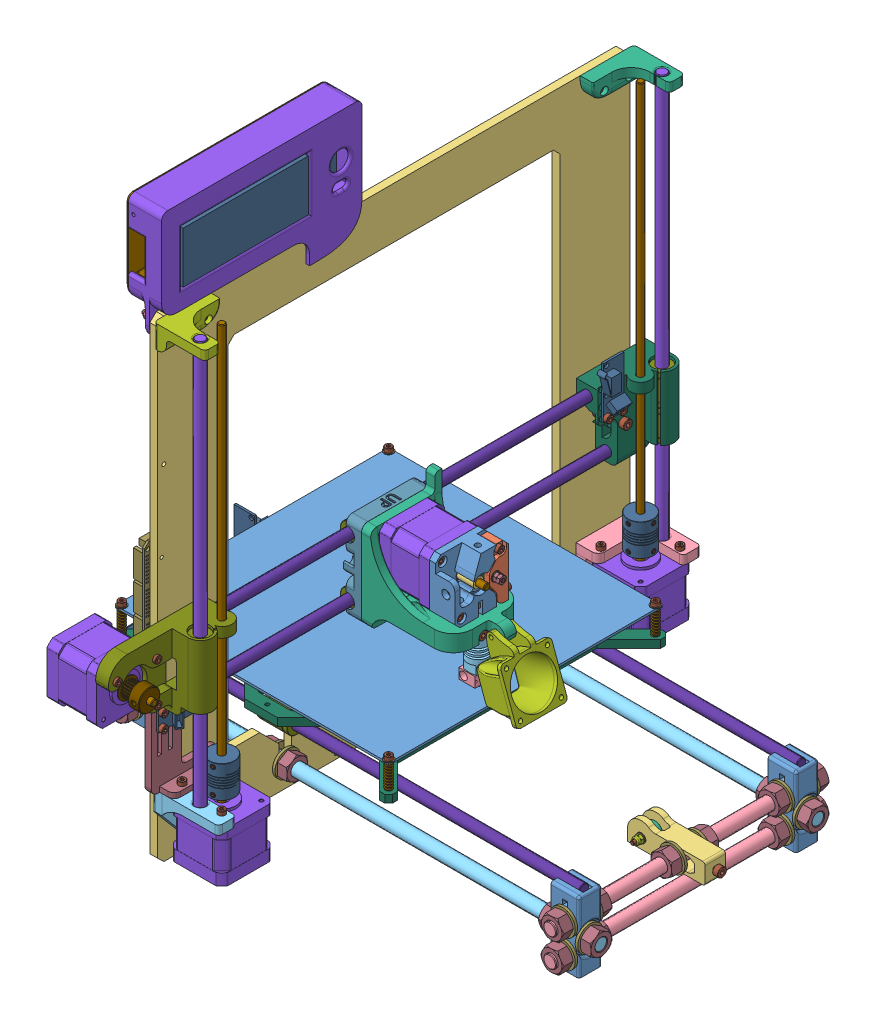
SolidWorks assembly PRUSAI3, configuration Default. Lengths in mm.
Overall size (404.17 477.46 509.56).
242 component instances, 46 part files, 23 mates.
Components (placement in the parent):
- Base-1: Base [Default] at origin size (404.17 86.77 210.4)
  - Base_corner-0.1-1: Base_corner-0.1 [Default] at origin size (22 55 18)
  - Base_corner-0.1-2: Base_corner-0.1 [Default] at (-318 0 -18) x (-1 0 0) z (0 0 -1) size (22 55 18)
  - Base_corner-0.1-3: Base_corner-0.1 [Default] at (0 0 -170) size (22 55 18)
  - Base_corner-0.1-4: Base_corner-0.1 [Default] at (-318 0 -188) x (-1 0 0) z (0 0 -1) size (22 55 18)
  - motor-holder.mod-1: motor-holder.mod [Default] at (-374.7251 51.5513 -101.8541) x (1 0 0) z (0 0 -1) size (87.93 49.87 10)
  - motor-idler.mod-1: motor-idler.mod [Default] at (-14.7612 34.4184 -85.8494) x (0 0 -1) z (0.003191 0.999995 0) size (16.01 60.81 19.45)
  - M10x210-Threaded_Rod-1: M10x210-Threaded_Rod [Default] at (-329 12 12) x (0.934388 0.356257 0) z (0 0 1) size (10 10 210)
  - M10x210-Threaded_Rod-2: M10x210-Threaded_Rod [Default] at (11 12 12) x (0.968928 -0.247345 0) z (0 0 1) size (10 10 210)
  - M10x210-Threaded_Rod-3: M10x210-Threaded_Rod [Default] at (11 34 12) size (10 10 210)
  - M10x210-Threaded_Rod-4: M10x210-Threaded_Rod [Default] at (-329 34 12) x (-0.101096 0.994877 0) z (0 0 1) size (10 10 210)
  - M10x380-Th_Rod-1: M10x380-Th_Rod [Default] at (30 23 -179) x (0 -0.123501 0.992344) z (1 0 0) size (10 10 380)
  - M10x380-Th_Rod-2: M10x380-Th_Rod [Default] at (30 23 -9) x (0 -0.445891 -0.895087) z (1 0 0) size (10 10 380)
  - 4mm Bearing SKF 624 RS 286-7798-1: 4mm Bearing SKF 624 RS 286-7798 [Default] at (-14.7612 34.4184 -96.1602) x (0 0 -1) z (0.767407 -0.641161 0) size (5 13 13)
  - Locking nut-1: Locking nut [DIN EN ISO 7040 - M3 - N] at (-14.7612 34.4184 -82.6956) x (0.998707 -0.050831 0) z (0 0 1) size (5.5 6.35 4.5)
  - Stepper_motor_NEMA17 39mm-1: Stepper_motor_NEMA17 39mm [Default] at (-296.4022 27.5 -99.8541) x (1 0 0) z (0 -1 0) size (42 63.3 42)
    - Stator-1: Stator [Default] at origin size (42 41.1 42)
    - Rotor-1: Rotor [Default] x (0.508449 0 0.861092) z (-0.861092 0 0.508449) size (21 60.8 21)
  - Mech endstop-1: Mech endstop [Default] at (-342.0588 64.8904 -101.8541) x (0 1 0) z (0 0 -1) size (40 21.02 12.37)
  - Socket head cap screw-2: Socket head cap screw [M3x25] at (-14.7612 34.4184 -106.281) x (0 0 1) z (0.238463 0.971152 0) size (28 5.5 5.5)
  - Socket head cap screw-1: Socket head cap screw [DIN 912 M4 x 20 --- 20N] at (40.3236 34.2427 -93.8494) x (-0.999995 0.003191 0) z (0.002674 0.838028 0.545621) size (24 7 7)
  - Socket head cap screw-3: Socket head cap screw [M3x12] at (-311.9022 43 -90.8541) x (0 0 -1) z (0.820112 0.572203 0) size (15 5.5 5.5)
  - Socket head cap screw-4: Socket head cap screw [M3x12] at (-311.9022 12 -90.8541) x (0 0 -1) z (1 0 0) size (15 5.5 5.5)
  - Socket head cap screw-5: Socket head cap screw [M3x12] at (-280.9022 12 -90.8541) x (0 0 -1) z (1 0 0) size (15 5.5 5.5)
  - Socket head cap screw-6: Socket head cap screw [M3x10] at (-336.5588 47.3904 -106.4541) x (0 0 1) z (-1 0 0) size (13 5.5 5.5)
  - Socket head cap screw-7: Socket head cap screw [M3x10] at (-347.5588 47.3904 -106.4541) x (0 0 1) z (-1 0 0) size (13 5.5 5.5)
  - Plain washer-1: Plain washer [M3 plain washer] at (-14.7612 34.4184 -85.5697) x (0 0 -1) z (0.726093 -0.687596 0) size (0.5 7 7)
  - Plain washer-2: Plain washer [M3 plain washer] at (-14.7612 34.4184 -100.668) x (0 0 -1) z (0.875249 -0.483673 0) size (0.5 7 7)
  - Plain washer-3: Plain washer [M10 plain washer] at (-224 23 -179) x (1 0 0) z (0 0.48884 0.872373) size (2 20 20)
  - Plain washer-4: Plain washer [M10 plain washer] at (0 23 -179) x (1 0 0) z (0 -0.109422 0.993995) size (2 20 20)
  - Plain washer-5: Plain washer [M10 plain washer] at (-216 23 -179) x (1 0 0) z (0 -0.107778 0.994175) size (2 20 20)
  - Plain washer-6: Plain washer [M10 plain washer] at (-316 23 -179) x (1 0 0) z (0 -0.430378 0.902649) size (2 20 20)
  - Plain washer-7: Plain washer [M10 plain washer] at (22 23 -179) x (1 0 0) z (0 -0.121982 0.992532) size (2 20 20)
  - Plain washer-8: Plain washer [M10 plain washer] at (-338 23 -179) x (1 0 0) z (0 -0.100121 0.994975) size (2 20 20)
  - Plain washer-15: Plain washer [M10 plain washer] at (11 34 -188) x (0 0 1) z (-0.882764 0.469816 0) size (2 20 20)
  - Plain washer-16: Plain washer [M10 plain washer] at (11 34 2) x (0 0 1) z (-0.957093 -0.28978 0) size (2 20 20)
  - Plain washer-17: Plain washer [M10 plain washer] at (11 12 -18) x (0 0 1) z (-0.957093 -0.28978 0) size (2 20 20)
  - Plain washer-18: Plain washer [M10 plain washer] at (11 34 -168) x (0 0 1) z (-0.809211 -0.587518 0) size (2 20 20)
  - Plain washer-19: Plain washer [M10 plain washer] at (11 34 -101.8494) x (0 0 1) z (-0.957093 -0.28978 0) size (2 20 20)
  - Plain washer-20: Plain washer [M10 plain washer] at (11 12 -168) x (0 0 1) z (-0.952122 -0.305719 0) size (2 20 20)
  - Plain washer-21: Plain washer [M10 plain washer] at (11 12 -188) x (0 0 1) z (-0.957093 -0.28978 0) size (2 20 20)
  - Plain washer-22: Plain washer [M10 plain washer] at (11 34 -18) x (0 0 1) z (-0.957093 -0.28978 0) size (2 20 20)
  - Plain washer-23: Plain washer [M10 plain washer] at (11 34 -83.8494) x (0 0 1) z (-0.957093 -0.28978 0) size (2 20 20)
  - Plain washer-24: Plain washer [M10 plain washer] at (11 12 2) x (0 0 1) z (-0.957093 -0.28978 0) size (2 20 20)
  - Plain washer-33: Plain washer [M10 plain washer] at (-329 12 -102.0906) x (0 0 1) z (-0.8302 -0.557466 0) size (2 20 20)
  - Plain washer-34: Plain washer [M10 plain washer] at (-329 34 -101.8541) x (0 0 1) z (-0.803588 0.595186 0) size (2 20 20)
  - Plain washer-35: Plain washer [M10 plain washer] at (-329 34 -89.8541) x (0 0 1) z (-0.998096 0.061678 0) size (2 20 20)
  - Plain washer-36: Plain washer [M10 plain washer] at (-329 12 -89.5517) x (0 0 1) z (-0.979431 0.201779 0) size (2 20 20)
  - Plain washer-39: Plain washer [M10 plain washer] at (-329 12 -188) x (0 0 1) z (-0.957093 -0.28978 0) size (2 20 20)
  - Plain washer-40: Plain washer [M10 plain washer] at (-329 34 -188) x (0 0 1) z (-0.957093 -0.28978 0) size (2 20 20)
  - Plain washer-41: Plain washer [M10 plain washer] at (-329 12 -168) x (0 0 1) z (-0.957093 -0.28978 0) size (2 20 20)
  - Plain washer-42: Plain washer [M10 plain washer] at (-329 34 -168) x (0 0 1) z (-0.957093 -0.28978 0) size (2 20 20)
  - Plain washer-47: Plain washer [M10 plain washer] at (-223.0717 23 -9) x (1 0 0) z (0 -0.28978 0.957093) size (2 20 20)
  - Plain washer-48: Plain washer [M10 plain washer] at (-215.0717 23 -9) x (1 0 0) z (0 -0.28978 0.957093) size (2 20 20)
  - Plain washer-43: Plain washer [M10 plain washer] at (-329 12 -18) x (0 0 1) z (-0.957093 -0.28978 0) size (2 20 20)
  - Plain washer-44: Plain washer [M10 plain washer] at (-329 34 -18) x (0 0 1) z (-0.957093 -0.28978 0) size (2 20 20)
  - Plain washer-45: Plain washer [M10 plain washer] at (-329 12 2) x (0 0 1) z (-0.957093 -0.28978 0) size (2 20 20)
  - Plain washer-46: Plain washer [M10 plain washer] at (-329 34 2) x (0 0 1) z (-0.957093 -0.28978 0) size (2 20 20)
  - Plain washer-37: Plain washer [M10 plain washer] at (11 12 -18) x (0 0 1) z (-0.957093 -0.28978 0) size (2 20 20)
  - Hex nut-1: Hex nut [M4 Hex Nut] at (21.2099 34.3037 -93.8494) x (0.001311 0.410701 0.911769) z (-0.999995 0.003191 0) size (7 8.08 3.2)
  - Hex nut-2: Hex nut [M3 Hex Nut] at (-336.5588 47.3904 -94.0203) x (0.985742 0.168264 0) z (0 0 1) size (5.5 6.35 2.4)
  - Hex nut-3: Hex nut [M3 Hex Nut] at (-347.5588 47.3904 -93.992) x (0.630761 -0.775977 0) z (0 0 1) size (5.5 6.35 2.4)
  - Hex nut-4: Hex nut [M10 Hex Nut] at (-329 12 -81.1517) x (0.998444 0.055764 0) z (0 0 1) size (16 18.48 8.4)
  - Hex nut-5: Hex nut [M10 Hex Nut] at (-329 34 -103.8541) x (0.98326 0.182209 0) z (0 0 1) size (16 18.48 8.4)
  - Hex nut-6: Hex nut [M10 Hex Nut] at (-329 34 -81.4541) size (16 18.48 8.4)
  - Hex nut-7: Hex nut [M10 Hex Nut] at (-329 12 -104.0906) x (0.982431 -0.186624 0) z (0 0 1) size (16 18.48 8.4)
  - Hex nut-8: Hex nut [M10 Hex Nut] at (-329 12 -159.6) x (0.697574 0.716512 0) z (0 0 1) size (16 18.48 8.4)
  - Hex nut-9: Hex nut [M10 Hex Nut] at (-329 34 10.4) x (0.514033 0.85777 0) z (0 0 1) size (16 18.48 8.4)
  - Hex nut-10: Hex nut [M10 Hex Nut] at (-329 12 -20) x (0.882857 0.469642 0) z (0 0 1) size (16 18.48 8.4)
  - Hex nut-11: Hex nut [M10 Hex Nut] at (-329 12 10.4) x (0.513305 0.858206 0) z (0 0 1) size (16 18.48 8.4)
  - Hex nut-12: Hex nut [M10 Hex Nut] at (-329 34 -20) x (0.752342 0.658773 0) z (0 0 1) size (16 18.48 8.4)
  - Hex nut-13: Hex nut [M10 Hex Nut] at (-329 12 -190) x (0.72852 0.685024 0) z (0 0 1) size (16 18.48 8.4)
  - Hex nut-14: Hex nut [M10 Hex Nut] at (-329 34 -159.6) x (0.559236 0.829009 0) z (0 0 1) size (16 18.48 8.4)
  - Hex nut-15: Hex nut [M10 Hex Nut] at (-329 34 -190) x (-0.791014 0.611798 0) z (0 0 1) size (16 18.48 8.4)
  - Hex nut-24: Hex nut [M10 Hex Nut] at (-234.4 23 -179) x (0 -0.116344 0.993209) z (-1 0 0) size (16 18.48 8.4)
  - Hex nut-25: Hex nut [M10 Hex Nut] at (-316 23 -9) x (0 -0.002508 0.999997) z (-1 0 0) size (16 18.48 8.4)
  - Hex nut-26: Hex nut [M10 Hex Nut] at (-348.4 23 -9) x (0 -0.059792 0.998211) z (-1 0 0) size (16 18.48 8.4)
  - Hex nut-27: Hex nut [M10 Hex Nut] at (-10.4 23 -9) x (0 -0.325908 0.945401) z (-1 0 0) size (16 18.48 8.4)
  - Hex nut-28: Hex nut [M10 Hex Nut] at (22 23 -9) x (0 -0.034286 0.999412) z (-1 0 0) size (16 18.48 8.4)
  - Hex nut-29: Hex nut [M10 Hex Nut] at (-316 23 -179) x (0 -0.095045 0.995473) z (-1 0 0) size (16 18.48 8.4)
  - Hex nut-30: Hex nut [M10 Hex Nut] at (-10.4 23 -179) x (0 -0.899521 0.436877) z (-1 0 0) size (16 18.48 8.4)
  - Hex nut-31: Hex nut [M10 Hex Nut] at (22 23 -179) x (0 -0.998594 0.053006) z (-1 0 0) size (16 18.48 8.4)
  - Hex nut-32: Hex nut [M10 Hex Nut] at (11 34 -103.8494) x (0.993461 -0.114176 0) z (0 0 1) size (16 18.48 8.4)
  - Hex nut-33: Hex nut [M10 Hex Nut] at (11 34 -75.4494) x (0.997282 0.073679 0) z (0 0 1) size (16 18.48 8.4)
  - Hex nut-35: Hex nut [M10 Hex Nut] at (-216 23 -179) x (0 0.262055 0.965053) z (-1 0 0) size (16 18.48 8.4)
  - Hex nut-36: Hex nut [M10 Hex Nut] at (-234.4 23 -9) x (0 -0.298029 0.954557) z (-1 0 0) size (16 18.48 8.4)
  - Hex nut-37: Hex nut [M10 Hex Nut] at (-216 23 -9) x (0 0.004098 0.999992) z (-1 0 0) size (16 18.48 8.4)
  - Hex nut-38: Hex nut [M10 Hex Nut] at (-348.4 23 -179) x (0 -0.766318 0.642462) z (-1 0 0) size (16 18.48 8.4)
  - Hex nut-39: Hex nut [M10 Hex Nut] at (11 34 -198.4) x (-0.053006 -0.998594 0) z (0 0 -1) size (16 18.48 8.4)
  - Hex nut-40: Hex nut [M10 Hex Nut] at (11 12 -198.4) x (-0.053006 -0.998594 0) z (0 0 -1) size (16 18.48 8.4)
  - Hex nut-41: Hex nut [M10 Hex Nut] at (11 12 10.4) x (0.053006 -0.998594 0) z (0 0 1) size (16 18.48 8.4)
  - Hex nut-42: Hex nut [M10 Hex Nut] at (11 34 10.4) x (0.053006 -0.998594 0) z (0 0 1) size (16 18.48 8.4)
  - Hex nut-43: Hex nut [M10 Hex Nut] at (11 34 -28.4) x (-0.053006 -0.998594 0) z (0 0 -1) size (16 18.48 8.4)
  - Hex nut-44: Hex nut [M10 Hex Nut] at (11 12 -159.6) x (0.053006 -0.998594 0) z (0 0 1) size (16 18.48 8.4)
  - Hex nut-45: Hex nut [M10 Hex Nut] at (11 34 -159.6) x (0.053006 -0.998594 0) z (0 0 1) size (16 18.48 8.4)
  - Hex nut-46: Hex nut [M10 Hex Nut] at (11 12 -28.4) x (-0.053006 -0.998594 0) z (0 0 -1) size (16 18.48 8.4)
  - GT2_20T-pulley-1: GT2_20T-pulley [Default] at (-296.4022 27.5 -92.6779) x (0 0 1) z (-0.937722 0.347387 0) size (17.3 17 17)
  - Plain washer-49: Plain washer [M10 plain washer] at (22 23 -9) x (1 0 0) z (0 -0.28978 0.957093) size (2 20 20)
  - Plain washer-50: Plain washer [M3 plain washer] at (-14.7612 34.4184 -102.3494) x (0 0 -1) z (0.875249 -0.483673 0) size (0.5 7 7)
- Heated bed-1: Heated bed [Default] at (49.9039 65.1257 -264.04) x (0 0 1) z (0 -1 0) size (220 350 58.21)
  - bed-frame-1: bed-frame [Default] at (0.04 55.9824 0.0355) size (220 220 6)
  - LMU8-1: LMU8 [Default] at (85.04 318.9895 11.6257) x (0 -1 0) z (-0.000862 0 1) size (24 15 15)
  - LMU8-2: LMU8 [Default] at (255.04 257.9489 11.6257) x (0 1 0) z (0 0 1) size (24 15 15)
  - LMU8-3: LMU8 [Default] at (85.04 224.4824 11.6257) x (0 1 0) z (-0.92596 0 0.377622) size (24 15 15)
  - 8x350-Sm_Rod-1: 8x350-Sm_Rod [Default] at (85.04 382.9039 11.6257) x (0.720427 0 -0.693531) z (0 1 0) size (8 8 350)
  - 8x350-Sm_Rod-2: 8x350-Sm_Rod [Default] at (255.04 32.9039 11.6257) x (0.743236 0 -0.669029) z (0 -1 0) size (8 8 350)
  - spring-1: spring [Default] at (274.54 375.4824 -17.9745) x (0.611768 -0.791037 0) z (-0.791037 -0.611768 0) size (5.71 21.23 5.77)
  - spring-3: spring [Default] at (274.54 166.4824 -17.9745) x (1 0 0) z (0 -1 0) size (5.71 21.23 5.77)
  - spring-5: spring [Default] at (65.54 166.4824 -17.9745) x (-0.878714 -0.477349 0) z (-0.477349 0.878714 0) size (5.71 21.23 5.77)
  - spring-7: spring [Default] at (65.54 375.4824 -17.9745) x (0.923817 0.382834 0) z (0.382834 -0.923817 0) size (5.71 21.23 5.77)
  - HEATBED MK2 200x200-1: HEATBED MK2 200x200 [Default] at (277.04 163.9824 -19.6745) x (-1 0 0) z (0 0 -1) size (214 214 1.7)
  - Plain washer-1: Plain washer [M3 plain washer] at (65.54 375.4824 -20.1745) x (0 0 -1) z (0.999794 -0.020314 0) size (0.5 7 7)
  - Socket head cap screw-1: Socket head cap screw [M3x25] at (65.54 375.4824 -23.1745) x (0 0 1) z (0.313828 -0.94948 0) size (28 5.5 5.5)
  - Socket head cap screw-2: Socket head cap screw [M3x25] at (65.54 166.4824 -23.1745) x (0 0 1) z (0.313828 -0.94948 0) size (28 5.5 5.5)
  - Plain washer-2: Plain washer [M3 plain washer] at (65.54 166.4824 -20.1745) x (0 0 -1) z (0.999794 -0.020314 0) size (0.5 7 7)
  - Plain washer-3: Plain washer [M3 plain washer] at (274.54 375.4824 -20.1745) x (0 0 -1) z (0.999794 -0.020314 0) size (0.5 7 7)
  - Plain washer-4: Plain washer [M3 plain washer] at (274.54 166.4824 -20.1745) x (0 0 -1) z (0.999794 -0.020314 0) size (0.5 7 7)
  - Socket head cap screw-3: Socket head cap screw [M3x25] at (274.54 375.4824 -23.1745) x (0 0 1) z (0.313828 -0.94948 0) size (28 5.5 5.5)
  - Socket head cap screw-4: Socket head cap screw [M3x25] at (274.54 166.4824 -23.1745) x (0 0 1) z (0.313828 -0.94948 0) size (28 5.5 5.5)
  - Y Belt Holder-1: Y Belt Holder [Default] at (178.0647 270.4824 20.5355) x (0 1 0) z (1 0 0) size (50 29 16)
  - Socket head cap screw-5: Socket head cap screw [M3x12] at (170.0647 290.9824 13.0355) x (0 0 -1) z (0.865356 -0.501158 0) size (15 5.5 5.5)
  - Socket head cap screw-9: Socket head cap screw [M3x12] at (170.0647 249.9824 13.0355) x (0 0 -1) z (0.844505 -0.535547 0) size (15 5.5 5.5)
- Frame-1: Frame [Default] at (-223.0717 3 91) x (0 0 -1) z (1 0 0) size (452.86 372.2 75.95)
  - main-frame-1: main-frame [Default] at origin size (370 370 6)
  - z-axis-bottom-DX-01-1: z-axis-bottom-DX-01 [Default] at (386.3431 55 -54) x (0 0 1) z (0 -1 0) size (51 114 38.29)
  - z-axis-bottom-SX-01-1: z-axis-bottom-SX-01 [Default] at (-13 55 -54) x (0 0 1) z (0 -1 0) size (52.5 47 38.29)
  - z-axis-top-DX-o1-1: z-axis-top-DX-o1 [Default] at (350 360 6) x (-1 0 0) z (0 0 -1) size (42.04 39.81 40)
  - z-axis-top-SX-o1-1: z-axis-top-SX-o1 [Default] at (100 360 6) x (-1 0 0) z (0 0 -1) size (126.01 39.81 40)
  - Stepper_motor_NEMA17 39mm-1: Stepper_motor_NEMA17 39mm [Default] at (349 50 35.3) size (42 63.3 42)
    - Stator-1: Stator [Default] at origin size (42 41.1 42)
    - Rotor-1: Rotor [Default] x (0.508449 0 0.861092) z (-0.861092 0 0.508449) size (21 60.8 21)
  - Stepper_motor_NEMA17 39mm-3: Stepper_motor_NEMA17 39mm [Default] at (21 50 35.3) size (42 63.3 42)
    - Stator-1: Stator [Default] at origin size (42 41.1 42)
    - Rotor-1: Rotor [Default] x (0.508449 0 0.861092) z (-0.861092 0 0.508449) size (21 60.8 21)
  - 8x320-Sm_Rod-1: 8x320-Sm_Rod [Default] at (4.2 50.0879 35.3) x (-0.788009 0 0.615663) z (0 -1 0) size (8 8 320)
  - M5x300-Th_Rod-1: M5x300-Th_Rod [Default] at (349 372.2 35.3) x (-0.54173 0 -0.840552) z (0 1 0) size (5 5 300)
  - Acople Flexible5.5-1: Acople Flexible5.5 [Default] at (124.2696 67.5 -54.8152) x (0.964915 0 -0.262561) z (0 -1 0) size (20.86 20.77 25)
    - Acople Flexible 5.5-1: Acople Flexible 5.5 [Predeterminado] at (-123.3071 59.8391 -12.5) size (20.77 20.77 25)
    - socket set screw cone point_am-1: socket set screw cone point_am [B18.3.6M - M3 x 0.5 x 6 Hex Socket Cone Pt. SS --N] at (-133.7812 59.8391 9.5) x (1 0 0) z (0 0.199151 0.979969) size (6 3 3)
    - socket set screw cone point_am-3: socket set screw cone point_am [B18.3.6M - M3 x 0.5 x 6 Hex Socket Cone Pt. SS --N] at (-123.3071 49.5232 -9.5) x (0 1 0) z (-0.430549 0 0.902567) size (6 3 3)
    - socket set screw cone point_am-5: socket set screw cone point_am [B18.3.6M - M3 x 0.5 x 6 Hex Socket Cone Pt. SS --N] at (-123.3071 49.5452 9.5) x (0 1 0) z (0.224681 0 0.974432) size (6 3 3)
    - socket set screw cone point_am-7: socket set screw cone point_am [B18.3.6M - M3 x 0.5 x 6 Hex Socket Cone Pt. SS --N] at (-133.6418 59.8391 -9.5) x (1 0 0) z (0 -0.210117 0.977676) size (6 3 3)
  - 8x320-Sm_Rod-3: 8x320-Sm_Rod [Default] at (365.8 50.0967 35.3) x (-0.483486 0 0.875352) z (0 -1 0) size (8 8 320)
  - M5x300-Th_Rod-3: M5x300-Th_Rod [Default] at (21 72.2 35.3) x (0.854838 0 0.518895) z (0 -1 0) size (5 5 300)
  - Acople Flexible5.5-3: Acople Flexible5.5 [Default] at (474.2049 67.5 91.0593) x (0.999461 0 -0.032825) z (0 1 0) size (20.86 20.77 25)
    - Acople Flexible 5.5-1: Acople Flexible 5.5 [Predeterminado] at (-123.3071 59.8391 -12.5) size (20.77 20.77 25)
    - socket set screw cone point_am-1: socket set screw cone point_am [B18.3.6M - M3 x 0.5 x 6 Hex Socket Cone Pt. SS --N] at (-133.7812 59.8391 9.5) x (1 0 0) z (0 0.199151 0.979969) size (6 3 3)
    - socket set screw cone point_am-3: socket set screw cone point_am [B18.3.6M - M3 x 0.5 x 6 Hex Socket Cone Pt. SS --N] at (-123.3071 49.5232 -9.5) x (0 1 0) z (-0.430549 0 0.902567) size (6 3 3)
    - socket set screw cone point_am-5: socket set screw cone point_am [B18.3.6M - M3 x 0.5 x 6 Hex Socket Cone Pt. SS --N] at (-123.3071 49.5452 9.5) x (0 1 0) z (0.224681 0 0.974432) size (6 3 3)
    - socket set screw cone point_am-7: socket set screw cone point_am [B18.3.6M - M3 x 0.5 x 6 Hex Socket Cone Pt. SS --N] at (-133.6418 59.8391 -9.5) x (1 0 0) z (0 -0.210117 0.977676) size (6 3 3)
  - ArduinoMega-1: ArduinoMega [Default] at (27.4632 161.2114 -6.651) x (0 -1 0) z (0 0 1) size (107.95 53.42 12.95)
  - end stop Z- support-1: end stop Z- support [Default] at (17.7233 80 7.3) size (53.55 60 16.5)
  - Socket head cap screw-1: Socket head cap screw [M3x10] at (340 360 13) x (0 0 -1) z (1 0 0) size (13 5.5 5.5)
  - Socket head cap screw-3: Socket head cap screw [M3x10] at (360 360 13) x (0 0 -1) z (1 0 0) size (13 5.5 5.5)
  - Socket head cap screw-5: Socket head cap screw [M3x25] at (30 360 13) x (0 0 -1) z (1 0 0) size (28 5.5 5.5)
  - Socket head cap screw-7: Socket head cap screw [M3x10] at (364.5 58 50.8) x (0 -1 0) z (-0.290933 0 0.956743) size (13 5.5 5.5)
  - Socket head cap screw-9: Socket head cap screw [M3x10] at (5.5 58 50.8) x (0 -1 0) z (0.997858 0 0.065425) size (13 5.5 5.5)
  - Socket head cap screw-11: Socket head cap screw [M3x14] at (5.9313 62 19.3515) x (0 -1 0) z (0.959191 0 0.28276) size (17 5.5 5.5)
  - Socket head cap screw-13: Socket head cap screw [M3x14] at (36.5086 62 19.8015) x (0 -1 0) z (-0.958116 0 -0.286382) size (17 5.5 5.5)
  - Socket head cap screw-15: Socket head cap screw [M3x10] at (364.5 58 19.8) x (0 -1 0) z (0 0 1) size (13 5.5 5.5)
  - Socket head cap screw-17: Socket head cap screw [M3x10] at (333.5 58 19.8) x (0 -1 0) z (-0.842603 0 -0.538535) size (13 5.5 5.5)
  - Socket head cap screw-19: Socket head cap screw [M3x25] at (10 360 13) x (0 0 -1) z (1 0 0) size (28 5.5 5.5)
  - Mech endstop-1: Mech endstop [Default] at (12.8486 105.0903 12.3134) size (40 21.02 12.37)
  - Socket head cap screw-20: Socket head cap screw [M3x10] at (-4.6514 110.5903 16.9134) x (0 0 -1) z (1 0 0) size (13 5.5 5.5)
  - Hex nut-1: Hex nut [M3 Hex Nut] at (-4.6514 99.5903 9.2201) x (0.999995 -0.003142 0) z (0 0 1) size (5.5 6.35 2.4)
  - Socket head cap screw-22: Socket head cap screw [M3x10] at (-4.6514 99.5903 16.9134) x (0 0 -1) z (1 -0.000192 0) size (13 5.5 5.5)
  - Hex nut-3: Hex nut [M3 Hex Nut] at (10 360 -10) x (-0.188876 -0.982001 0) z (0 0 1) size (5.5 6.35 2.4)
  - Hex nut-5: Hex nut [M3 Hex Nut] at (30 360 -10) x (0.958903 -0.283734 0) z (0 0 1) size (5.5 6.35 2.4)
  - Hex nut-7: Hex nut [M3 Hex Nut] at (-4.6514 110.5903 9.2248) x (0.958903 -0.283734 0) z (0 0 1) size (5.5 6.35 2.4)
- Traverse axis-1: Traverse axis [Default] at (-205.1894 146.9626 -92.4317) x (0 0 1) z (-1 0 0) size (443.18 81.92 98.02)
  - X-CARRIAGE_Universal-0.1-1: X-CARRIAGE_Universal-0.1 [Default] at (21.9957 -0.8838 -0.419) size (71.43 75.53 72.93)
  - end-idler-0.1-1: end-idler-0.1 [Default] at (-152.8642 29.1162 5.081) x (0 1 0) z (1 0 0) size (60 40.87 54)
  - end-motor-0.1-1: end-motor-0.1 [Default] at (227.7275 27.6162 5.081) x (-1 0 0) z (0 1 0) size (109.4 31.99 65.52)
  - 8x370-Sm_Rod-1: 8x370-Sm_Rod [Default] at (-182.9646 21.6162 -3.419) x (0 0.354283 0.935138) z (-1 0 0) size (8 8 370)
  - 8x370-Sm_Rod-2: 8x370-Sm_Rod [Default] at (-182.9646 -23.3838 -3.419) x (0 -0.426874 -0.904311) z (-1 0 0) size (8 8 370)
  - Socket head cap screw-1: Socket head cap screw [M3x12] at (201.3267 -17.3838 -6.919) x (0 0 1) z (-1 0 0) size (15 5.5 5.5)
  - Socket head cap screw-2: Socket head cap screw [M3x12] at (232.3267 13.6162 -6.919) x (0 0 1) z (-1 0 0) size (15 5.5 5.5)
  - Socket head cap screw-3: Socket head cap screw [M3x12] at (201.3267 13.6162 -6.919) x (0 0 1) z (-1 0 0) size (15 5.5 5.5)
  - Socket head cap screw-4: Socket head cap screw [DIN 912 M4 x 20 --- 20N] at (-157.3642 -1.8838 -15.919) x (0 0 1) z (0.55411 0.832443 0) size (24 7 7)
  - Socket head cap screw-5: Socket head cap screw [M3x10] at (-142.7007 9.5193 -16.6079) x (0 0 1) z (-0.431421 0.902151 0) size (13 5.5 5.5)
  - Socket head cap screw-6: Socket head cap screw [M3x10] at (-153.7006 9.4905 -16.6079) x (0 0 1) z (-0.975917 -0.218143 0) size (13 5.5 5.5)
  - Mech endstop-1: Mech endstop [Default] at (-148.2465 27.0048 -12.0079) x (-0.002619 0.999997 0) z (0 0 -1) size (40 21.02 12.37)
  - Stepper_motor_NEMA17 39mm-1: Stepper_motor_NEMA17 39mm [Default] at (216.8267 -1.8838 3.081) x (1 0 0) z (0 1 0) size (42 63.3 42)
    - Stator-1: Stator [Default] at origin size (42 41.1 42)
    - Rotor-1: Rotor [Default] x (0.508449 0 0.861092) z (-0.861092 0 0.508449) size (21 60.8 21)
  - Hex nut-1: Hex nut [M5 Hex Nut] at (-166.1768 21.4162 -17) x (-0.498592 0 -0.866837) z (0 -1 0) size (8 9.24 4.7)
  - Hex nut-2: Hex nut [M5 Hex Nut] at (162.2275 19.9162 -17.419) x (0.999996 0 0.002672) z (0 -1 0) size (8 9.24 4.7)
  - Hex nut-3: Hex nut [M4 Hex Nut] at (-157.3642 -1.8838 7.804) x (0.504676 0.863309 0) z (0 0 1) size (7 8.08 3.2)
  - Hex nut-4: Hex nut [M3 Hex Nut] at (-142.7007 9.5193 -5.4494) x (0.857251 -0.514899 0) z (0 0 1) size (5.5 6.35 2.4)
  - Hex nut-6: Hex nut [M3 Hex Nut] at (-153.7006 9.4905 -5.4473) x (0.868758 0.495237 0) z (0 0 1) size (5.5 6.35 2.4)
  - 4mm Bearing SKF 624 RS 286-7798-1: 4mm Bearing SKF 624 RS 286-7798 [Default] at (-157.3642 -1.8838 -0.3791) x (0 0 1) z (-0.999674 0.025514 0) size (5 13 13)
  - GT2_20T-pulley 5mm bore-1: GT2_20T-pulley 5mm bore [Default] at (216.8267 -1.8838 -2.9492) x (0 0 -1) z (0.999848 0.01741 0) size (17.3 17 17)
  - LMU8-5: LMU8 [Default] at (-182.3684 27.1162 -17.4178) x (0 -1 0) z (-0.165895 0 0.986143) size (24 15 15)
  - LMU8-6: LMU8 [Default] at (179.2316 1.6162 -17.4178) x (0 -1 0) z (0 0 1) size (24 15 15)
  - LMU8-1: LMU8 [Default] at (-2.2947 21.6162 -3.419) x (1 0 0) z (0 -0.01536 0.999882) size (24 15 15)
  - LMU8-4: LMU8 [Default] at (-2.2947 -23.3838 -3.419) x (1 0 0) z (0 -0.01536 0.999882) size (24 15 15)
  - LMU8-2: LMU8 [Default] at (24.2053 21.6162 -3.419) x (1 0 0) z (0 -0.01536 0.999882) size (24 15 15)
  - LMU8-3: LMU8 [Default] at (24.2053 -23.3838 -3.419) x (1 0 0) z (0 -0.01536 0.999882) size (24 15 15)
  - LMU8-7: LMU8 [Default] at (179.2316 25.6162 -17.4178) x (0 -1 0) z (-0.591671 0 0.80618) size (24 15 15)
  - LMU8-8: LMU8 [Default] at (-182.3684 3.1162 -17.4178) x (0 -1 0) z (-0.98242 0 0.186681) size (24 15 15)
- ExtruderDD1-1: ExtruderDD1 [Default] at (-124.6705 159.0788 -70.436) x (0 0 -1) z (1 0 0) size (45.82 42.02 65.09)
  - DD-1 extruder-1: DD-1 extruder [Default] at origin size (42 42 20)
  - DD-1 Idler-1: DD-1 Idler [Default] at (21.0104 18.9837 0) x (0.002967 0.999996 0) z (0 0 1) size (39.57 15 15)
  - Stepper_motor_NEMA17 39mm-1: Stepper_motor_NEMA17 39mm [Default] at (0 0 -18) x (1 0 0) z (0 -1 0) size (42 63.3 42)
    - Stator-1: Stator [Default] at origin size (42 41.1 42)
    - Rotor-1: Rotor [Default] x (0.508449 0 0.861092) z (-0.861092 0 0.508449) size (21 60.8 21)
  - Hex nut-1: Hex nut [M3 Hex Nut] at (-1.8851 -15.1119 -4) x (0 0 1) z (-1 0 0) size (5.5 6.35 2.4)
  - Socket head cap screw-1: Socket head cap screw [M3x10] at (-15.5 15.5 -16.3) x (0 0 -1) z (0.417389 0.908728 0) size (13 5.5 5.5)
  - Socket head cap screw-3: Socket head cap screw [M3x25] at (24.8182 -15.1119 -4) x (-1 0 0) z (0 0.898586 -0.438797) size (28 5.5 5.5)
  - Socket head cap screw-5: Socket head cap screw [M3x20] at (-15.5 -15.5 -1.3) x (0 0 -1) z (0.998489 -0.054943 0) size (23 5.5 5.5)
  - Socket head cap screw-7: Socket head cap screw [M3x20] at (15.5 15.5 0) x (0 0 -1) z (-0.467841 0.883812 0) size (23 5.5 5.5)
  - MK8 hobbed gear-1: MK8 hobbed gear [Default] at (0 0 -2.5414) x (0.957517 0.288377 0) z (0 0 1) size (8 8 13)
  - 4mm Bearing SKF 624 RS 286-7798-1: 4mm Bearing SKF 624 RS 286-7798 [Default] at (10.954 0.0134 -9.5568) x (0 0 -1) z (0.991845 -0.127452 0) size (5 13 13)
  - Socket head cap screw-8: Socket head cap screw [M3x16] at (10.954 0.0134 -13.0115) x (0 0 1) z (-0.999739 -0.022865 0) size (19 5.5 5.5)
  - Plain washer-1: Plain washer [M3 plain washer] at (10.954 0.0134 -10.0115) x (0 0 -1) z (0.919176 0.393848 0) size (0.5 7 7)
  - Plain washer-2: Plain washer [M3 plain washer] at (10.954 0.0134 -4) x (0 0 1) z (-0.416652 -0.909066 0) size (0.5 7 7)
  - Plain washer-4: Plain washer [M3 plain washer] at (10.954 0.0134 0.5) x (0 0 1) z (-0.857912 -0.513797 0) size (0.5 7 7)
  - Hex nut-2: Hex nut [M3 Hex Nut] at (10.954 0.0134 5.5618) x (0.990359 -0.138525 0) z (0 0 1) size (5.5 6.35 2.4)
  - Hex nut-4: Hex nut [M3 Hex Nut] at (10.954 0.0134 2.9968) x (0.998532 -0.054169 0) z (0 0 1) size (5.5 6.35 2.4)
  - Plain washer-6: Plain washer [M3 plain washer] at (21.8182 -15.1119 -4) x (1 0 0) z (0 -0.909066 0.416652) size (0.5 7 7)
- Jhead-1: Jhead [Default] at (-131.6705 88.0788 -74.436) x (0 0 1) z (-1 0 0) size (16.36 51 16.68)
  - Nozzle-1: Nozzle [Default] at origin size (12.5 21 12.5)
  - PEEK body-1: PEEK body [Default] at (0 8 0) x (0.999743 0 -0.022686) z (0.022686 0 0.999743) size (16 40 16)
- DD1support-1: DD1support [Default] at (-183.7705 153.7788 -70.436) x (0 0 -1) z (1 0 0) size (55.98 115.8 123.55)
  - DD1support-1: DD1support [Default] at origin size (55.98 81.92 84.98)
  - Hex nut-1: Hex nut [M4 Hex Nut] at (-11.5 3.8 0) size (7 8.08 3.2)
  - Hex nut-5: Hex nut [M4 Hex Nut] at (11.5 3.8 0) size (7 8.08 3.2)
  - Hex nut-8: Hex nut [M4 Hex Nut] at (-11.4063 -28.7 51.6) x (1 0 0) z (0 -1 0) size (7 8.08 3.2)
  - Hex nut-9: Hex nut [M4 Hex Nut] at (-4.1461 -24.8 38.6431) size (7 8.08 3.2)
  - Hex nut-10: Hex nut [M4 Hex Nut] at (12.1461 -24.8 38.6431) x (0.983219 -0.182428 0) z (0 0 1) size (7 8.08 3.2)
  - Socket head cap screw-1: Socket head cap screw [M4x15] at (-4.1461 -24.8 64.5) x (0 0 -1) z (-0.956022 -0.293294 0) size (19 7 7)
  - Socket head cap screw-3: Socket head cap screw [M4x15] at (12.1461 -24.8 64.5) x (0 0 -1) z (0.382249 -0.924059 0) size (19 7 7)
  - Hex nut-11: Hex nut [M4 Hex Nut] at (-11.5 -19.2 0) size (7 8.08 3.2)
  - Hex nut-12: Hex nut [M4 Hex Nut] at (11.5 -19.2 0) size (7 8.08 3.2)
  - FUN-DUCT-0.1-1: FUN-DUCT-0.1 [Default] at (4.0244 -45.3084 96.0105) x (-1 0 0) z (0 -0.34202 -0.939693) size (42.99 53.77 46.81)
  - Stepper_motor_NEMA17 39mm-1: Stepper_motor_NEMA17 39mm [Default] at (0.0671 5.3 41.1) x (1 0 0) z (0 -1 0) size (42 63.3 42)
    - Stator-1: Stator [Default] at origin size (42 41.1 42)
    - Rotor-1: Rotor [Default] x (0.508449 0 0.861092) z (-0.861092 0 0.508449) size (21 60.8 21)
- composizione-2: composizione [Default] at (-229.9717 431.3641 190.7952) x (0 0 -1) z (1 0 0) size (237.29 129.09 28.21)
  - frontale-1: frontale [Default] at (178.2952 -16.7641 2) x (-1 0 0) z (0 0 -1) size (158.86 94.86 26)
  - tappo-1: tappo [Default] at (203.2236 -43.3754 -10) x (-1 0 0) z (0 0 -1) size (157 73 12.41)
  - base-1: base [Default] at (177.7952 -17.7641 0.3) size (237.29 129.09 15.7)
Mates (geometry in assembly coordinates):
- Concentric1: concentric anti-aligned: cylinder of Base-1/Base_corner-0.1-1 through (20 53.5 -9) axis (-1 0 0) radius 4; cylinder of Heated bed-1/8x350-Sm_Rod-2 through (-333 53.5 -9) axis (1 0 0) radius 4
- Distance1: distance = 3 mm anti-aligned: plane of Base-1/Base_corner-0.1-1 through (20 53.5 -9) normal (-1 0 0); plane of Heated bed-1/8x350-Sm_Rod-2 through (17 53.5 -9) normal (1 0 0)
- Parallel4: parallel aligned: plane of Heated bed-1/bed-frame-1 through (-6.0786 65.0902 -264) normal (0 1 0); plane of assembly through (0 0 0) normal (0 1 0)
- Concentric2: concentric anti-aligned: cylinder of Base-1/M10x380-Th_Rod-1 through (-350 23 -179) axis (1 0 0) radius 5; cylinder of Frame-1/main-frame-1 through (-217.0717 23 -179) axis (-1 0 0) radius 5
- Concentric3: concentric anti-aligned: cylinder of Base-1/M10x380-Th_Rod-2 through (-350 23 -9) axis (1 0 0) radius 5; cylinder of Frame-1/main-frame-1 through (-217.0717 23 -9) axis (-1 0 0) radius 5
- Coincident1: coincident anti-aligned: plane of ? through (-218 32.9417 -7.9222) normal (-1 0 0); plane of Frame-1/main-frame-1 through (-218 3 91) normal (1 0 0)
- Coincident2: coincident anti-aligned: axis of Frame-1/8x320-Sm_Rod-1 through (-187.7717 372.5879 86.8) axis (0 -1 0); axis of Traverse axis-1/end-motor-0.1-1 through (-187.7717 124.5788 86.8) axis (0 1 0)
- Coincident3: coincident anti-aligned: axis of Frame-1/8x320-Sm_Rod-3 through (-187.7717 372.5967 -274.8) axis (0 -1 0); axis of Traverse axis-1/end-idler-0.1-1 through (-187.7717 126.0788 -274.8) axis (0 1 0)
- Parallel5: parallel anti-aligned: plane of Traverse axis-1/X-CARRIAGE_Universal-0.1-1 through (-190.7705 180.0788 -98.436) normal (1 0 0); plane of ExtruderDD1-1/Stepper_motor_NEMA17 39mm-1/Stator-1 through (-183.7705 159.0788 -97.136) normal (-1 0 0)
- Coincident4: coincident anti-aligned: axis of ExtruderDD1-1/DD-1 extruder-1 through (-131.6705 174.4779 -74.436) axis (0 -1 0); axis of Jhead-1/PEEK body-1 through (-131.6705 131.2788 -74.436) axis (0 1 0)
- Coincident5: coincident anti-aligned: plane of Traverse axis-1/X-CARRIAGE_Universal-0.1-1 through (-190.7705 180.0788 -98.436) normal (1 0 0); plane of DD1support-1/DD1support-1 through (-190.7705 153.7788 -70.436) normal (-1 0 0)
- Concentric6: concentric aligned: cylinder of ExtruderDD1-1/DD-1 extruder-1 through (-131.6705 180.0789 -74.436) axis (0 -1 0) radius 1.1; cylinder of DD1support-1/DD1support-1 through (-131.6705 141.6143 -74.436) axis (0 -1 0) radius 1.25
- Coincident6: coincident anti-aligned: plane of ExtruderDD1-1/DD-1 extruder-1 through (-139.6705 138.0788 -91.436) normal (0 -1 0); plane of DD1support-1/DD1support-1 through (-248.2367 138.0788 -42.436) normal (0 1 0)
- Concentric7: concentric anti-aligned: cylinder of ExtruderDD1-1/DD-1 extruder-1 through (-131.6705 180.0789 -74.436) axis (0 -1 0) radius 1.1; cylinder of Jhead-1/PEEK body-1 through (-131.6705 96.0788 -74.436) axis (0 1 0) radius 3
- Coincident7: coincident anti-aligned: plane of Jhead-1/PEEK body-1 through (-131.8519 136.0788 -82.4339) normal (0 1 0); plane of DD1support-1/DD1support-1 through (-131.6705 136.0788 -74.436) normal (0 -1 0)
- Coincident8: coincident aligned: plane of Traverse axis-1/X-CARRIAGE_Universal-0.1-1 through (-190.7705 180.0788 -98.436) normal (0 1 0); plane of ExtruderDD1-1/DD-1 extruder-1 through (-139.6705 180.0788 -91.436) normal (0 1 0)
- Coincident9: coincident aligned: plane of Traverse axis-1/X-CARRIAGE_Universal-0.1-1 through (-204.7705 146.0788 -42.436) normal (0 0 1); plane of DD1support-1/DD1support-1 through (-190.7705 112.0687 -42.436) normal (0 0 1)
- Coincident10: coincident anti-aligned: plane of Frame-1/main-frame-1 through (-223.0717 3 91) normal (-1 0 0); plane of ? through (-223.0717 365.1 79) normal (1 0 0)
- Concentric8: concentric aligned: cylinder of Frame-1/Socket head cap screw-19 through (-178.3217 363 81) axis (1 0 0) radius 1.5; cylinder of composizione-2/frontale-1 through (-232.1717 363 81) axis (1 0 0) radius 1.25
- Concentric9: concentric aligned: cylinder of Frame-1/Socket head cap screw-5 through (-178.3217 363 61) axis (1 0 0) radius 1.5; cylinder of composizione-2/frontale-1 through (-232.1717 363 61) axis (1 0 0) radius 1.25
- Parallel6: parallel aligned: plane of Jhead-1/Nozzle-1 through (-127.6705 96.0788 -80.686) normal (1 0 0); plane of DD1support-1/DD1support-1 through (-118.7705 153.7788 -70.436) normal (1 0 0)
- Coincident32: coincident anti-aligned: plane of Frame-1/main-frame-1 through (-223.0717 3 91) normal (-1 0 0); plane of Base-1/Plain washer-47 through (-223.0717 28.0247 -7.4787) normal (1 0 0)
- Coincident33: coincident anti-aligned: plane of Frame-1/main-frame-1 through (-217.0717 3 91) normal (1 0 0); circle of Base-1/Plain washer-48
